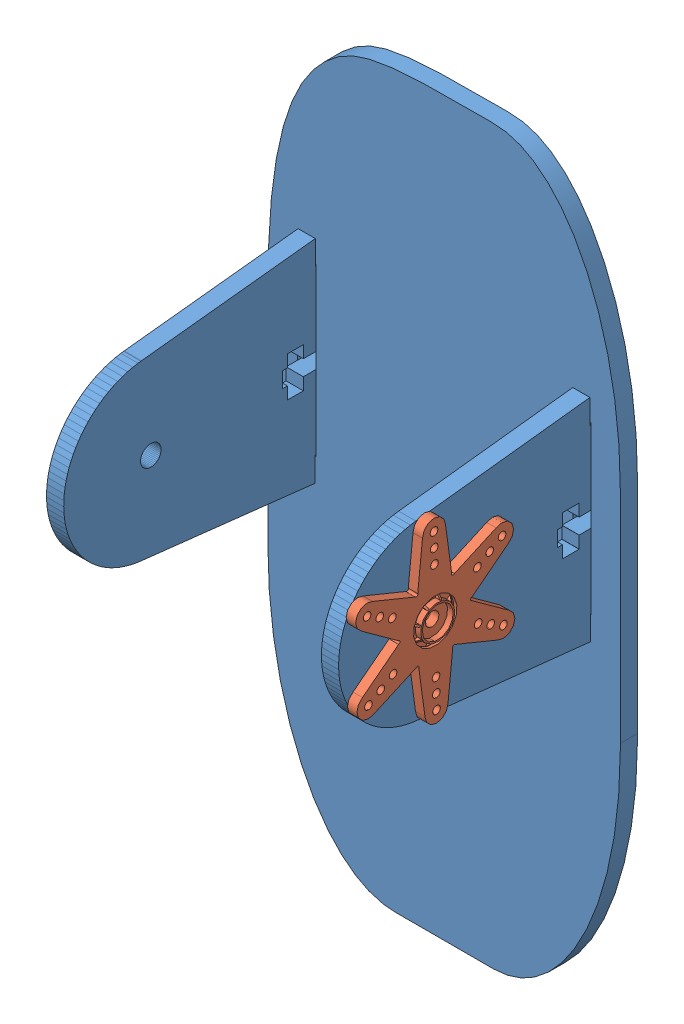
SolidWorks assembly Assem2, configuration Default. Lengths in mm.
Overall size (79.99 157.44 61.01).
2 component instances, 2 part files, 2 mates.
Components (placement in the parent):
- left_foot_100-4: left_foot_100 [Default] at origin size (79.99 157.44 54.86)
- servo_arm_6_sided-1: servo_arm_6_sided [Default] at (64.5213 89.3668 37.105) x (0 0.513695 -0.857973) z (0 -0.857973 -0.513695) size (36.45 6.25 32.2)
Mates (geometry in assembly coordinates):
- Coincident4: coordinate: point of left_foot_100-4
- ProfileCenter1: profile center aligned: circle of left_foot_100-4; circle of servo_arm_6_sided-1
